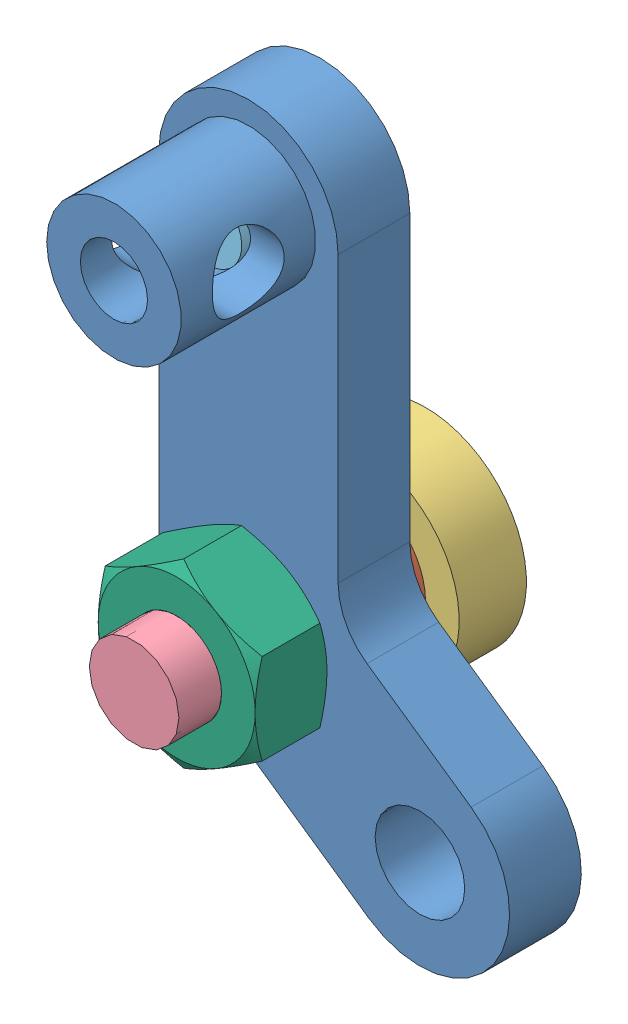
SolidWorks assembly PressingArm, configuration Default. Lengths in mm.
Overall size (16.15 29.66 14.9).
6 component instances, 6 part files, 8 mates.
Components (placement in the parent):
- alavanca-1: alavanca [Default] at (-16.0981 -6.8202 2.7607) size (15.65 29.66 9.2)
- BrassBush-1: BrassBush [Default] at (-16.0981 -6.8202 2.7607) x (-0.923728 -0.383049 0) z (0 0 -1) size (6 6 4.7)
- bear 9 x 5 x 3mm-1: bear 9 x 5 x 3mm [Default] at (-16.0981 -6.8202 -1.9393) size (9 9 3)
- FlatScrew-2: FlatScrew [B18.6.7M - M4 x 0.7 x 13 Slotted PHMS --13N] at (-16.0981 -6.8202 -5.0393) x (0 0 1) z (-1 0 0) size (14 6 6)
- Flat Head Screw_AM-1: Flat Head Screw_AM [B18.6.7M - M3 x 0.5 x 5 Type I Cross Recessed FHMS --5N] at (-16.0981 9.5298 2.7607) x (0 0 1) z (-0.923728 -0.383049 0) size (5 5.5 5.5)
- Hex Nut Style 1_AM-1: Hex Nut Style 1_AM [B18.2.4.1M - Hex nut, Style 1,  M4 x 0.7 --D-N] at (-16.0981 -6.8202 9.1607) size (7 8.08 3.2)
Mates (geometry in assembly coordinates):
- Coincident2: coincident anti-aligned: circle of BrassBush-1; circle of bear 9 x 5 x 3mm-1
- Concentric1: concentric anti-aligned: cylinder of alavanca-1 through (-16.0981 -6.8202 5.9607) axis (0 0 -1) radius 1.65; cylinder of BrassBush-1 through (-16.0981 -6.8202 1.0607) axis (0 0 1) radius 2
- Coincident3: coincident anti-aligned: plane of alavanca-1 through (-16.0981 9.5298 2.7607) normal (0 0 -1); plane of BrassBush-1 through (-16.0981 -6.8202 2.7607) normal (0 0 1)
- Concentric2: concentric aligned: cylinder of bear 9 x 5 x 3mm-1 through (-16.0981 -6.8202 1.0607) axis (0 0 -1) radius 2.5; cylinder of FlatScrew-2 through (-16.0981 -6.8202 -30.4393) axis (0 0 -1) radius 2
- Coincident4: coincident anti-aligned: plane of bear 9 x 5 x 3mm-1 through (-16.0981 -6.8202 -1.9393) normal (0 0 -1); plane of FlatScrew-2 through (-16.0981 -4.8202 -1.9393) normal (0 0 1)
- Coincident51: coincident aligned: plane of Flat Head Screw_AM-1 through (-16.0981 9.5298 2.7607) normal (0 0 -1); plane of alavanca-1 through (-16.0981 9.5298 2.7607) normal (0 0 -1)
- Concentric3: concentric anti-aligned: cylinder of FlatScrew-2 through (-16.0981 -6.8202 -30.4393) axis (0 0 -1) radius 2; cylinder of Hex Nut Style 1_AM-1 through (-16.0981 -6.8202 -15.8768) axis (0 0 1) radius 2
- Coincident6: coincident anti-aligned: plane of alavanca-1 through (-16.0981 9.5298 5.9607) normal (0 0 1); plane of Hex Nut Style 1_AM-1 through (-16.0981 -2.7787 5.9607) normal (0 0 -1)
